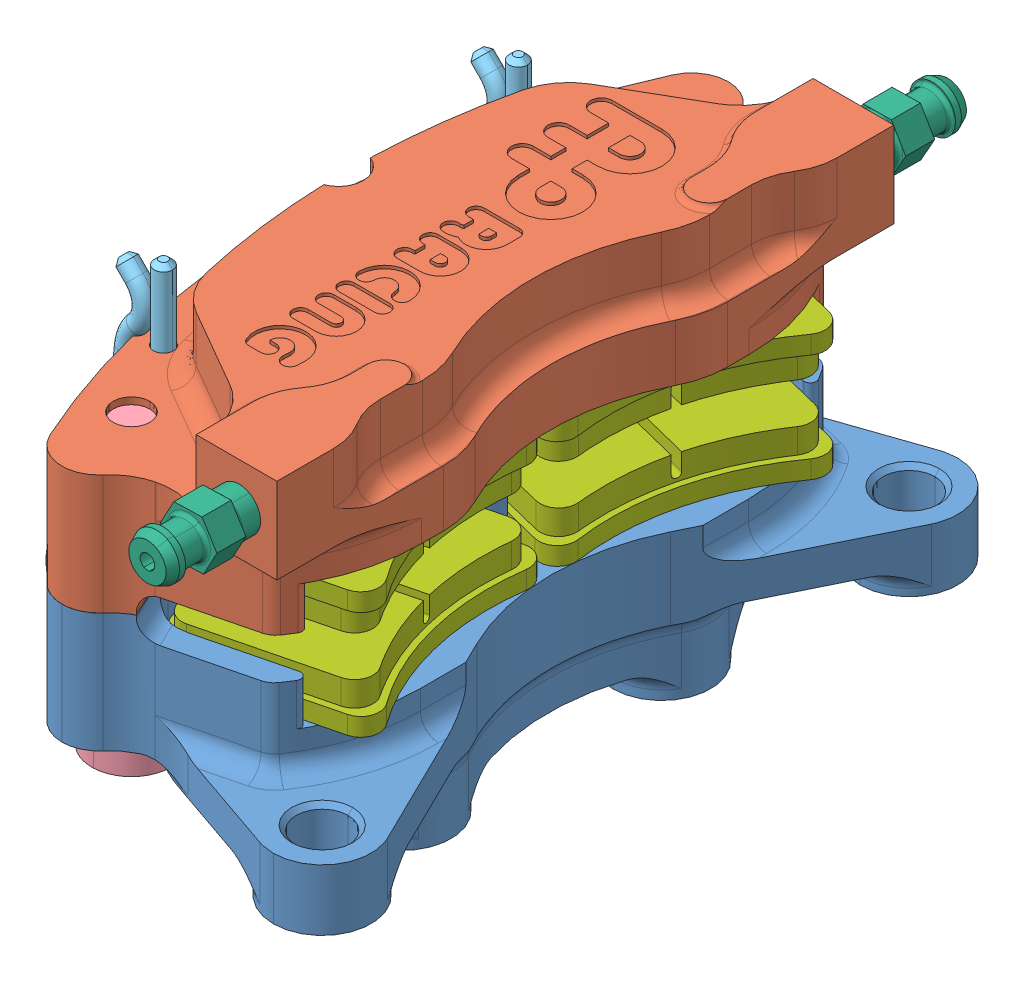
SolidWorks assembly FR-CP4227-2S0, configuration Default. Lengths in mm.
Overall size (71.54 66.42 130.94).
18 component instances, 7 part files, 0 mates.
Components (placement in the parent):
- CP4227-2S0.STEP-1: CP4227-2S0.STEP [Default] x (0 0 -1) z (0 -1 0) size (130.94 71.54 66.42)
  - CP4227-101.STEP-1: CP4227-101.STEP [Default] at origin size (112 60.5 34.68)
  - CP4227-102.STEP-1: CP4227-102.STEP [Default] x (-1 0 0) z (0 0 -1) size (109 47.57 30.98)
  - cp3049-40a_CP4226-103.STEP-1: cp3049-40a_CP4226-103.STEP [Default] at (-23.4668 -94.12 -10.305) size (25.2 25.2 14.87)
  - cp3049-40a_CP4226-103.STEP-2: cp3049-40a_CP4226-103.STEP [Default] at (-23.4668 -94.12 10.305) x (-0.98369 0.179874 0) z (0 0 -1) size (25.2 25.2 14.87)
  - cp3049-40a_CP4226-103.STEP-3: cp3049-40a_CP4226-103.STEP [Default] at (23.4668 -94.12 10.305) x (-0.960147 0.279495 0) z (0 0 -1) size (25.2 25.2 14.87)
  - cp3049-40a_CP4226-103.STEP-4: cp3049-40a_CP4226-103.STEP [Default] at (23.4668 -94.12 -10.305) size (25.2 25.2 14.87)
  - cp3838-M08x1.25m_CP4477-110.STEP-1: cp3838-M08x1.25m_CP4477-110.STEP [Default] at (-41.1 -109.6 19.55) x (-0.998897 0.046962 0) z (0 0 -1) size (13 13 46)
  - cp3838-M08x1.25m_CP4477-110.STEP-2: cp3838-M08x1.25m_CP4477-110.STEP [Default] at (0 -116.83 19.55) x (-0.99038 0.138378 0) z (0 0 -1) size (13 13 46)
  - cp3838-M08x1.25m_CP4477-110.STEP-3: cp3838-M08x1.25m_CP4477-110.STEP [Default] at (41.1 -109.6 19.55) x (-1 -0.000032 0) z (0 0 -1) size (13 13 46)
  - cp4226-104_CP4226-104.STEP-1: cp4226-104_CP4226-104.STEP [Default] at (-29.0318 -116.44 -31.75) x (0 0 1) z (1 0 0) size (61.35 20.1 3)
  - cp4226-104_CP4226-104.STEP-2: cp4226-104_CP4226-104.STEP [Default] at (29.0318 -116.44 -31.75) x (0 0 1) z (1 0 0) size (61.35 20.1 3)
  - CP4469-101.STEP-1: CP4469-101.STEP [Default] at (-65.47 -82.62 -23.98) x (0 0.474307 -0.88036) z (1 0 0) size (9.24 8.21 29.15)
  - CP4469-101.STEP-2: CP4469-101.STEP [Default] at (65.47 -82.62 -23.98) x (0 0.509894 0.860237) z (-1 0 0) size (9.24 8.21 29.15)
  - CP4226-4m.STEP-1: CP4226-4m.STEP [Default] at (10.0433 -40.2815 10.305) x (0.970296 0.241922 0) z (0 0 -1) size (39.7 43.64 7)
  - CP4226-4m.STEP-2: CP4226-4m.STEP [Default] at (10.0433 -40.2815 -10.305) x (-0.970296 -0.241922 0) z (0 0 1) size (39.7 43.64 7)
  - CP4226-4m.STEP-3: CP4226-4m.STEP [Default] at (-10.0433 -40.2815 -10.305) x (-0.970296 0.241922 0) z (0 0 1) size (39.7 43.64 7)
  - CP4226-4m.STEP-4: CP4226-4m.STEP [Default] at (-10.0433 -40.2815 10.305) x (0.970296 -0.241922 0) z (0 0 -1) size (39.7 43.64 7)
